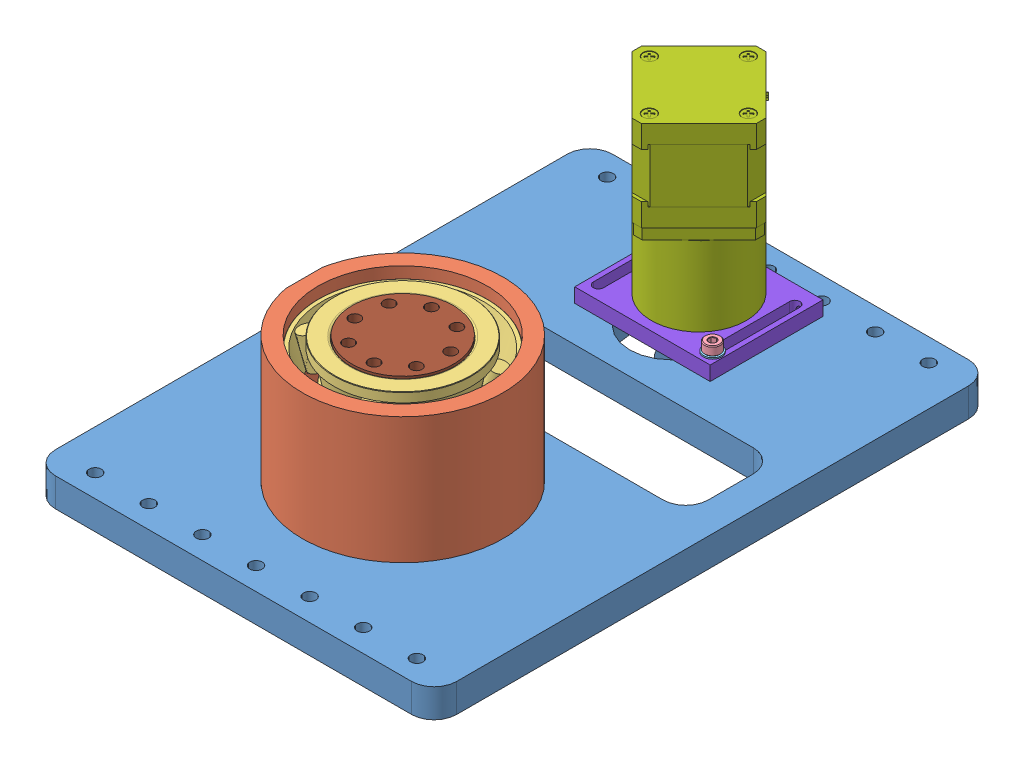
SolidWorks assembly UOR23-ARM-2-A-002_Base, configuration Default. Lengths in mm.
Overall size (177.81 118.86 246.81).
14 component instances, 13 part files, 32 mates.
Components (placement in the parent):
- UOR23-ARM-2-P-015-3: UOR23-ARM-2-P-015 [Default] at (0 -6.35 48.4048) x (0 0 -1) z (0 1 0) size (246.81 177.81 12.7)
- UOR23-ARM-P-017-1: UOR23-ARM-P-017 [Default] at (0 62.35 48.4048) x (1 0 0) z (0 -1 0) size (88.9 88.9 60)
- Bearing 32009X-1: Bearing 32009X [Default] at (0 41.85 48.4048) x (0 1 0) z (0.895204 0 -0.445657) size (20 75 75)
- Bearing 32009X-3: Bearing 32009X [Default] at (0 22.85 48.4048) x (0 -1 0) z (-0.960931 0 0.276789) size (20 75 75)
- 91292A043_TYPE 18-8 SS SOCKET HEAD CAP SCREW-1: 91292A043_TYPE 18-8 SS SOCKET HEAD CAP SCREW [91292A043] at (25.5 -4.7 -63.3452) x (1 0 0) z (0 -1 0) size (7 7 22.79)
- 98689A113_ METRIC GENERAL PURPOSE WASHERS-1: 98689A113_ METRIC GENERAL PURPOSE WASHERS [98689A113] at (25.5 13.3 -63.3452) x (1 0 0) z (0 -1 0) size (8 8 0.6)
- 93070A101_LOW-PROFILE SOCKET HEAD CAP SCREW-1: 93070A101_LOW-PROFILE SOCKET HEAD CAP SCREW [93070A101] at (0 2.65 89.4048) x (0 1 0) z (-0.995715 0 -0.092472) size (13.2 7 7)
- 17HS15-1684D-HG10-AR3-1: 17HS15-1684D-HG10-AR3 [Default] at (0 52.7 -82.7878) x (0.707107 0 -0.707107) z (0 -1 0) size (42.88 42 103.5)
- UOR23-ARM-2-A-P-016-1: UOR23-ARM-2-A-P-016 [Default] at (0 12.7 -82.7878) x (1 0 0) z (0 -1 0) size (60 50 6.35)
- 92125A190_TYPE 18-8 SS FLAT-HEAD SOCKET CAP SCREW-1: 92125A190_TYPE 18-8 SS FLAT-HEAD SOCKET CAP SCREW [92125A190] at (12.3744 6.75 -70.4134) x (-0.146393 0 -0.989226) z (0 -1 0) size (8 8 10.39)
- Pulley 15T-1: Pulley 15T [Default] at (0 -26.159 -82.7878) x (-0.056727 0 0.99839) z (-0.99839 0 -0.056727) size (28 25 28)
- UOR23-ARM-P-016-1: UOR23-ARM-P-016 [Default] at (0 62.35 48.4048) x (-0.513295 0 0.858212) z (0 -1 0) size (50 50 83)
- Pulley 60T-1: Pulley 60T [Default] at (0 -19.809 48.4048) x (0 -1 0) z (-0.243894 0 -0.969802) size (12.7 96.5 96.5)
- 92095A227_BUTTON HEAD HEX DRIVE SCREW-1: 92095A227_BUTTON HEAD HEX DRIVE SCREW [92095A227] at (-16.3489 -25.268 38.6265) x (0.837169 0 0.546944) z (0 -1 0) size (10.5 10.5 17.66)
Mates (geometry in assembly coordinates):
- Symmetric1: symmetric aligned: plane of assembly through (0 0 0) normal (1 0 0); plane of UOR23-ARM-2-P-015-3 through (88.904 253.2348 123.4048) normal (1 0 0); plane of UOR23-ARM-2-P-015-3 through (-88.904 253.2348 123.4048) normal (-1 0 0)
- Symmetric4: symmetric aligned: plane of UOR23-ARM-2-P-015-3 through (0 6.35 48.4048) normal (0 1 0); plane of UOR23-ARM-2-P-015-3 through (0 -6.35 48.4048) normal (0 -1 0)
- Symmetric5: symmetric aligned: plane of UOR23-ARM-2-P-015-3 through (-95 -6.35 123.4048) normal (0 0 1); plane of UOR23-ARM-2-P-015-3 through (75 -6.35 -123.4048) normal (0 0 -1)
- Coincident11: coincident anti-aligned: plane of UOR23-ARM-2-P-015-3 through (0 2.35 48.4048) normal (0 1 0); plane of UOR23-ARM-P-017-1 through (44.45 2.35 48.4048) normal (0 -1 0)
- Concentric1: concentric aligned: cylinder of UOR23-ARM-2-P-015-3 through (0 -6.35 89.4048) axis (0 -1 0) radius 2.25; cylinder of UOR23-ARM-P-017-1 through (0 2.35 89.4048) axis (0 -1 0) radius 1.65
- Concentric2: concentric anti-aligned: cylinder of UOR23-ARM-P-017-1 through (0 2.35 48.4048) axis (0 1 0) radius 37.5; cylinder of Bearing 32009X-1 through (0 41.85 48.4048) axis (0 -1 0) radius 37.5
- Concentric3: concentric aligned: cylinder of UOR23-ARM-2-P-015-3 through (0 2.35 48.4048) axis (0 1 0) radius 44.45; cylinder of UOR23-ARM-P-017-1 through (0 2.35 48.4048) axis (0 1 0) radius 44.45
- Concentric4: concentric aligned: cylinder of UOR23-ARM-P-017-1 through (0 2.35 48.4048) axis (0 1 0) radius 37.5; cylinder of Bearing 32009X-3 through (0 22.85 48.4048) axis (0 1 0) radius 37.5
- Coincident15: coincident anti-aligned: plane of UOR23-ARM-P-017-1 through (37.5 41.85 48.4048) normal (0 1 0); plane of Bearing 32009X-1 through (14.2248 41.85 76.9786) normal (0 -1 0)
- Coincident16: coincident anti-aligned: plane of UOR23-ARM-P-017-1 through (32 22.85 48.4048) normal (0 -1 0); plane of Bearing 32009X-3 through (8.8348 22.85 79.0765) normal (0 1 0)
- Concentric5: concentric anti-aligned: cylinder of 91292A043_TYPE 18-8 SS SOCKET HEAD CAP SCREW-1 through (25.5 17.3 -63.3452) axis (0 -1 0) radius 3.5; cylinder of 98689A113_ METRIC GENERAL PURPOSE WASHERS-1 through (25.5 12.7 -63.3452) axis (0 1 0) radius 4
- Coincident17: coincident anti-aligned: plane of 91292A043_TYPE 18-8 SS SOCKET HEAD CAP SCREW-1 through (25.5 13.3 -63.3452) normal (0 -1 0); plane of 98689A113_ METRIC GENERAL PURPOSE WASHERS-1 through (25.5 13.3 -63.3452) normal (0 1 0)
- Concentric6: concentric aligned: cylinder of 17HS15-1684D-HG10-AR3-1 through (0 5.4 -82.7878) axis (0 1 0) radius 4; cylinder of Pulley 15T-1 through (0 -28.3218 -82.7878) axis (0 1 0) radius 4
- Concentric7: concentric aligned: cylinder of 17HS15-1684D-HG10-AR3-1 through (0 12.7 -82.7878) axis (0 1 0) radius 21; cylinder of UOR23-ARM-2-A-P-016-1 through (0 12.7 -82.7878) axis (0 1 0) radius 12.5
- Coincident21: coincident anti-aligned: plane of 17HS15-1684D-HG10-AR3-1 through (0 12.7 -82.7878) normal (0 -1 0); plane of UOR23-ARM-2-A-P-016-1 through (0 12.7 -82.7878) normal (0 1 0)
- Concentric12: concentric aligned: cylinder of 17HS15-1684D-HG10-AR3-1 through (12.3744 12.7 -70.4134) axis (0 -1 0) radius 2.25; cylinder of 92125A190_TYPE 18-8 SS FLAT-HEAD SOCKET CAP SCREW-1 through (12.3744 6.75 -70.4134) axis (0 -1 0) radius 4
- Coincident22: coincident anti-aligned: plane of UOR23-ARM-2-P-015-3 through (0 6.35 48.4048) normal (0 1 0); plane of UOR23-ARM-2-A-P-016-1 through (0 6.35 -82.7878) normal (0 -1 0)
- Parallel2: parallel aligned: plane of UOR23-ARM-2-P-015-3 through (88.904 253.2348 123.4048) normal (1 0 0); plane of UOR23-ARM-2-A-P-016-1 through (30 6.35 -57.7878) normal (1 0 0)
- Width2: width aligned: plane of UOR23-ARM-2-A-P-016-1 through (30 6.35 -57.7878) normal (1 0 0); plane of UOR23-ARM-2-A-P-016-1 through (-30 6.35 -107.7878) normal (-1 0 0); plane of UOR23-ARM-2-P-015-3 through (88.904 253.2348 123.4048) normal (1 0 0); plane of UOR23-ARM-2-P-015-3 through (-88.904 253.2348 123.4048) normal (-1 0 0)
- Coincident23: coincident aligned: cone of UOR23-ARM-2-A-P-016-1 through (12.3744 6.35 -70.4134) axis (0 1 0); cone of 92125A190_TYPE 18-8 SS FLAT-HEAD SOCKET CAP SCREW-1 through (12.3744 9.05 -70.4134) axis (0 1 0)
- Concentric14: concentric anti-aligned: cylinder of UOR23-ARM-2-P-015-3 through (25.5 6.35 -63.3452) axis (0 1 0) radius 1.65; cylinder of 91292A043_TYPE 18-8 SS SOCKET HEAD CAP SCREW-1 through (25.5 17.3 -63.3452) axis (0 -1 0) radius 3.5
- Coincident24: coincident anti-aligned: plane of 98689A113_ METRIC GENERAL PURPOSE WASHERS-1 through (25.5 12.7 -63.3452) normal (0 -1 0); plane of UOR23-ARM-2-A-P-016-1 through (0 12.7 -82.7878) normal (0 1 0)
- Concentric15: concentric anti-aligned: cylinder of UOR23-ARM-P-016-1 through (0 60.1872 48.4048) axis (0 -1 0) radius 22.4917; cylinder of Pulley 60T-1 through (0 -28.3218 48.4048) axis (0 1 0) radius 12.7
- Coincident26: coincident anti-aligned: plane of UOR23-ARM-P-016-1 through (-12.8324 -19.8128 69.8601) normal (0 -1 0); plane of Pulley 60T-1 through (-42.184 -19.8128 59.0135) normal (0 1 0)
- Coincident27: coincident anti-aligned: plane of Pulley 60T-1 through (-12.3165 -24.1308 51.5022) normal (0 -1 0); plane of 92095A227_BUTTON HEAD HEX DRIVE SCREW-1 through (-13.4775 -24.1308 34.2314) normal (0 1 0)
- Concentric16: concentric anti-aligned: cylinder of Pulley 60T-1 through (-16.3489 -19.8128 38.6265) axis (0 1 0) radius 3.175; cylinder of 92095A227_BUTTON HEAD HEX DRIVE SCREW-1 through (-16.3489 -27.4308 38.6265) axis (0 -1 0) radius 5.25
- Concentric17: concentric anti-aligned: cylinder of UOR23-ARM-P-016-1 through (9.7783 -19.8128 32.0558) axis (0 -1 0) radius 2.5; cylinder of Pulley 60T-1 through (9.7783 -19.8128 32.0558) axis (0 1 0) radius 3.175
- Concentric18: concentric aligned: cylinder of Bearing 32009X-1 through (0 41.85 48.4048) axis (0 -1 0) radius 22.5; cylinder of UOR23-ARM-P-016-1 through (0 60.1872 48.4048) axis (0 -1 0) radius 22.4917
- Concentric20: concentric anti-aligned: cylinder of UOR23-ARM-2-P-015-3 through (0 -6.35 89.4048) axis (0 -1 0) radius 4.125; cylinder of 93070A101_LOW-PROFILE SOCKET HEAD CAP SCREW-1 through (0 -2.35 89.4048) axis (0 1 0) radius 3.5
- Coincident28: coincident anti-aligned: plane of UOR23-ARM-2-P-015-3 through (0 -2.35 87.1548) normal (0 -1 0); plane of 93070A101_LOW-PROFILE SOCKET HEAD CAP SCREW-1 through (0.3237 -2.35 85.9198) normal (0 1 0)
- Coincident29: coincident aligned: plane of Pulley 15T-1 through (0 -28.3218 -82.7878) normal (0 -1 0); plane of Pulley 60T-1 through (0 -28.3218 48.4048) normal (0 -1 0)
- Coincident30: coincident aligned: plane of UOR23-ARM-P-017-1 through (0 62.35 48.4048) normal (0 1 0); plane of UOR23-ARM-P-016-1 through (0 62.35 48.4048) normal (0 1 0)
